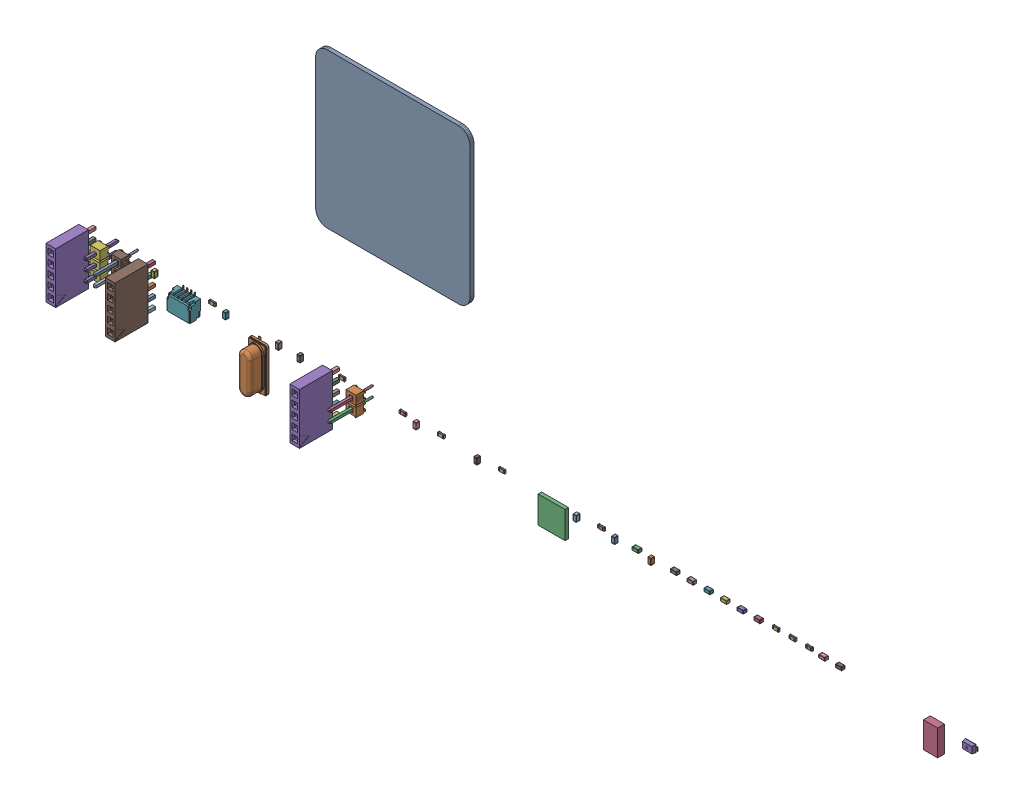
SolidWorks assembly RP2040-CRSF-Controller, configuration Default. Lengths in mm.
Overall size (232.87 85.74 11.8).
39 component instances, 11 part files, 0 mates.
Components (placement in the parent):
- RP2040-CRSF-Controller_BOARD-1: RP2040-CRSF-Controller_BOARD [Default] at origin size (40 40 1)
- ABLS_ABLS-12.000MHZ-B4-T-1-1: ABLS_ABLS-12.000MHZ-B4-T-1 [Default] at (221.3102 72.4916 0.9827) x (0 1 0) z (0 0 1) size (12.7 4.7 4.2)
- QFN40P700X700X90_HS-57N_CMP-020-00023-1-1: QFN40P700X700X90_HS-57N_CMP-020-00023-1 [Default] at (297.7388 76.962 0.9827) size (7 7 0.9)
- SOT230P700X180-4N_CMP-019-00050-5-1: SOT230P700X180-4N_CMP-019-00050-5 [Default] at (396.7734 77.2414 0.9827) size (3.7 6.7 1.78)
- RESC0603(1608)_L_CMP-009-00176-3-1: RESC0603(1608)_L_CMP-009-00176-3 [Default] at (209.2706 80.4672 0.9827) size (1.6 0.8 0.45)
- RESC0603(1608)_L_CMP-009-00176-3-2: RESC0603(1608)_L_CMP-009-00176-3 [Default] at (242.8494 80.4672 0.9827) size (1.6 0.8 0.45)
- RESC0603(1608)_L_CMP-009-00176-3-3: RESC0603(1608)_L_CMP-009-00176-3 [Default] at (258.5974 80.4672 0.9827) size (1.6 0.8 0.45)
- RESC0603(1608)_L_CMP-009-00176-3-4: RESC0603(1608)_L_CMP-009-00176-3 [Default] at (268.5288 80.4672 0.9827) size (1.6 0.8 0.45)
- RESC0603(1608)_L_CMP-009-00176-3-5: RESC0603(1608)_L_CMP-009-00176-3 [Default] at (284.2768 80.4672 0.9827) size (1.6 0.8 0.45)
- RESC0603(1608)_L_CMP-009-00176-3-6: RESC0603(1608)_L_CMP-009-00176-3 [Default] at (310.007 80.4672 0.9827) size (1.6 0.8 0.45)
- RESC0603(1608)_L_CMP-009-00176-3-7: RESC0603(1608)_L_CMP-009-00176-3 [Default] at (355.2444 80.4672 0.9827) size (1.6 0.8 0.45)
- RESC0603(1608)_L_CMP-009-00176-3-8: RESC0603(1608)_L_CMP-009-00176-3 [Default] at (359.5624 80.4672 0.9827) size (1.6 0.8 0.45)
- RESC0603(1608)_L_CMP-009-00176-3-9: RESC0603(1608)_L_CMP-009-00176-3 [Default] at (363.8804 80.4672 0.9827) size (1.6 0.8 0.45)
- RHDR5W74P0X254_1X5_1320X250X850P_2212S-05SG-85-1-1: RHDR5W74P0X254_1X5_1320X250X850P_2212S-05SG-85-1 [Default] at (175.641 68.8848 0.9827) x (0 1 0) z (0 0 1) size (13.2 2.5 11.6)
- RHDR5W74P0X254_1X5_1320X250X850P_2212S-05SG-85-1-2: RHDR5W74P0X254_1X5_1320X250X850P_2212S-05SG-85-1 [Default] at (191.0334 68.8848 0.9827) x (0 1 0) z (0 0 1) size (13.2 2.5 11.6)
- RHDR5W74P0X254_1X5_1320X250X850P_2212S-05SG-85-1-3: RHDR5W74P0X254_1X5_1320X250X850P_2212S-05SG-85-1 [Default] at (238.7854 68.8848 0.9827) x (0 1 0) z (0 0 1) size (13.2 2.5 11.6)
- SMTC-TSW-102-26-XX-S_CMP-1024-00327-1-1: SMTC-TSW-102-26-XX-S_CMP-1024-00327-1 [Default] at (186.6138 76.835 0.9827) x (0 1 0) z (0 0 1) size (5.21 2.54 11.58)
- SMTC-TSW-102-26-XX-S_CMP-1024-00327-1-2: SMTC-TSW-102-26-XX-S_CMP-1024-00327-1 [Default] at (247.4214 76.835 0.9827) x (0 1 0) z (0 0 1) size (5.21 2.54 11.58)
- TSW-103-XX-YY-S_TSW-103-26-G-S-1-1: TSW-103-XX-YY-S_TSW-103-26-G-S-1 [Default] at (180.9496 73.5076 0.9827) x (0 1 0) z (0 0 1) size (7.75 2.54 8.51)
- SM04B-SRSS-TB(LFSN)_SM04B-SRSS-TB_LF___SN-1-1: SM04B-SRSS-TB(LFSN)_SM04B-SRSS-TB_LF___SN-1 [Default] at (200.0758 75.2602 0.9827) size (6 4.95 2.96)
- PMEG2010ER115_PMEG2010ER,115-1-1: PMEG2010ER115_PMEG2010ER,115-1 [Default] at (405.511 79.1972 0.9827) size (3.5 2 1.07)
- CAPC0603(1608)100_L_CMP-001-00075-4-1: CAPC0603(1608)100_L_CMP-001-00075-4 [Default] at (194.4624 79.8068 0.9827) x (0 1 0) z (0 0 1) size (1.6 0.8 0.95)
- CAPC0603(1608)100_L_CMP-001-00075-4-2: CAPC0603(1608)100_L_CMP-001-00075-4 [Default] at (212.9536 79.8068 0.9827) x (0 1 0) z (0 0 1) size (1.6 0.8 0.95)
- CAPC0603(1608)100_L_CMP-001-00075-4-3: CAPC0603(1608)100_L_CMP-001-00075-4 [Default] at (226.6188 79.8068 0.9827) x (0 1 0) z (0 0 1) size (1.6 0.8 0.95)
- CAPC0603(1608)100_L_CMP-001-00075-4-4: CAPC0603(1608)100_L_CMP-001-00075-4 [Default] at (232.2068 79.8068 0.9827) x (0 1 0) z (0 0 1) size (1.6 0.8 0.95)
- CAPC0603(1608)100_L_CMP-001-00075-4-5: CAPC0603(1608)100_L_CMP-001-00075-4 [Default] at (262.2804 79.8068 0.9827) x (0 1 0) z (0 0 1) size (1.6 0.8 0.95)
- CAPC0603(1608)100_L_CMP-001-00075-4-6: CAPC0603(1608)100_L_CMP-001-00075-4 [Default] at (278.0284 79.8068 0.9827) x (0 1 0) z (0 0 1) size (1.6 0.8 0.95)
- CAPC0603(1608)100_L_CMP-001-00075-4-7: CAPC0603(1608)100_L_CMP-001-00075-4 [Default] at (303.7586 79.8068 0.9827) x (0 1 0) z (0 0 1) size (1.6 0.8 0.95)
- CAPC0603(1608)100_L_CMP-001-00075-4-8: CAPC0603(1608)100_L_CMP-001-00075-4 [Default] at (313.69 79.8068 0.9827) x (0 1 0) z (0 0 1) size (1.6 0.8 0.95)
- CAPC0603(1608)100_L_CMP-001-00075-4-9: CAPC0603(1608)100_L_CMP-001-00075-4 [Default] at (323.088 79.8068 0.9827) x (0 1 0) z (0 0 1) size (1.6 0.8 0.95)
- CAPC0603(1608)100_L_CMP-001-00075-4-10: CAPC0603(1608)100_L_CMP-001-00075-4 [Default] at (319.4304 80.4672 0.9827) size (1.6 0.8 0.95)
- CAPC0603(1608)100_L_CMP-001-00075-4-11: CAPC0603(1608)100_L_CMP-001-00075-4 [Default] at (350.9264 80.4672 0.9827) size (1.6 0.8 0.95)
- CAPC0603(1608)100_L_CMP-001-00075-4-12: CAPC0603(1608)100_L_CMP-001-00075-4 [Default] at (346.6084 80.4672 0.9827) size (1.6 0.8 0.95)
- CAPC0603(1608)100_L_CMP-001-00075-4-13: CAPC0603(1608)100_L_CMP-001-00075-4 [Default] at (342.2904 80.4672 0.9827) size (1.6 0.8 0.95)
- CAPC0603(1608)100_L_CMP-001-00075-4-14: CAPC0603(1608)100_L_CMP-001-00075-4 [Default] at (337.9724 80.4672 0.9827) size (1.6 0.8 0.95)
- CAPC0603(1608)100_L_CMP-001-00075-4-15: CAPC0603(1608)100_L_CMP-001-00075-4 [Default] at (333.6544 80.4672 0.9827) size (1.6 0.8 0.95)
- CAPC0603(1608)100_L_CMP-001-00075-4-16: CAPC0603(1608)100_L_CMP-001-00075-4 [Default] at (329.3364 80.4672 0.9827) size (1.6 0.8 0.95)
- CAPC0603(1608)100_L_CMP-001-00075-4-17: CAPC0603(1608)100_L_CMP-001-00075-4 [Default] at (367.7412 80.4672 0.9827) size (1.6 0.8 0.95)
- CAPC0603(1608)100_L_CMP-001-00075-4-18: CAPC0603(1608)100_L_CMP-001-00075-4 [Default] at (372.0592 80.4672 0.9827) size (1.6 0.8 0.95)
